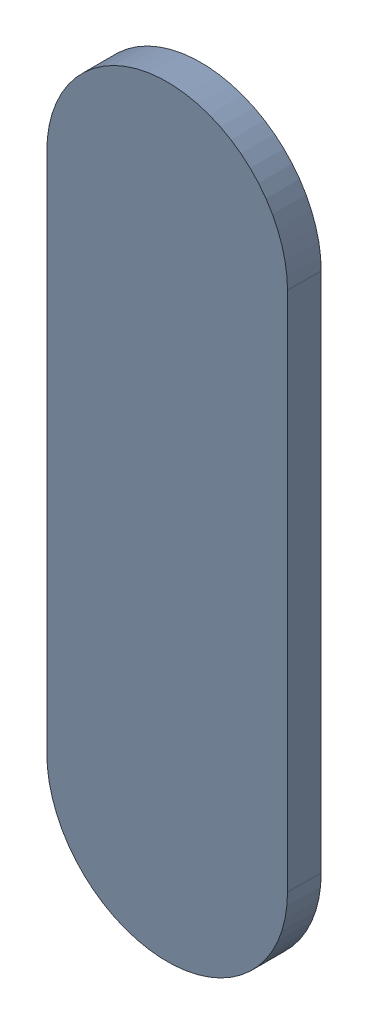
SolidWorks assembly Track (28.05mm,40.95mm)(28.05mm,41.5mm) on Top Layer, configuration Predeterminado. Lengths in mm.
Overall size (0.25 0.8 0.04).
2 component instances, 1 part files, 0 mates.
Components (placement in the parent):
- Track (28.05mm,40.95mm)(28.05mm,41.5mm) on Top Layer-1-1: Track (28.05mm,40.95mm)(28.05mm,41.5mm) on Top Layer-1 [Predeterminado] at (-68.317 -44.187 -0.0457) size (0.25 0.8 0.04)
  - Track (28.05mm,40.95mm)(28.05mm,41.5mm) on Top Layer-Part-1-1: Track (28.05mm,40.95mm)(28.05mm,41.5mm) on Top Layer-Part-1 [Predeterminado] at origin size (0.25 0.8 0.04)
